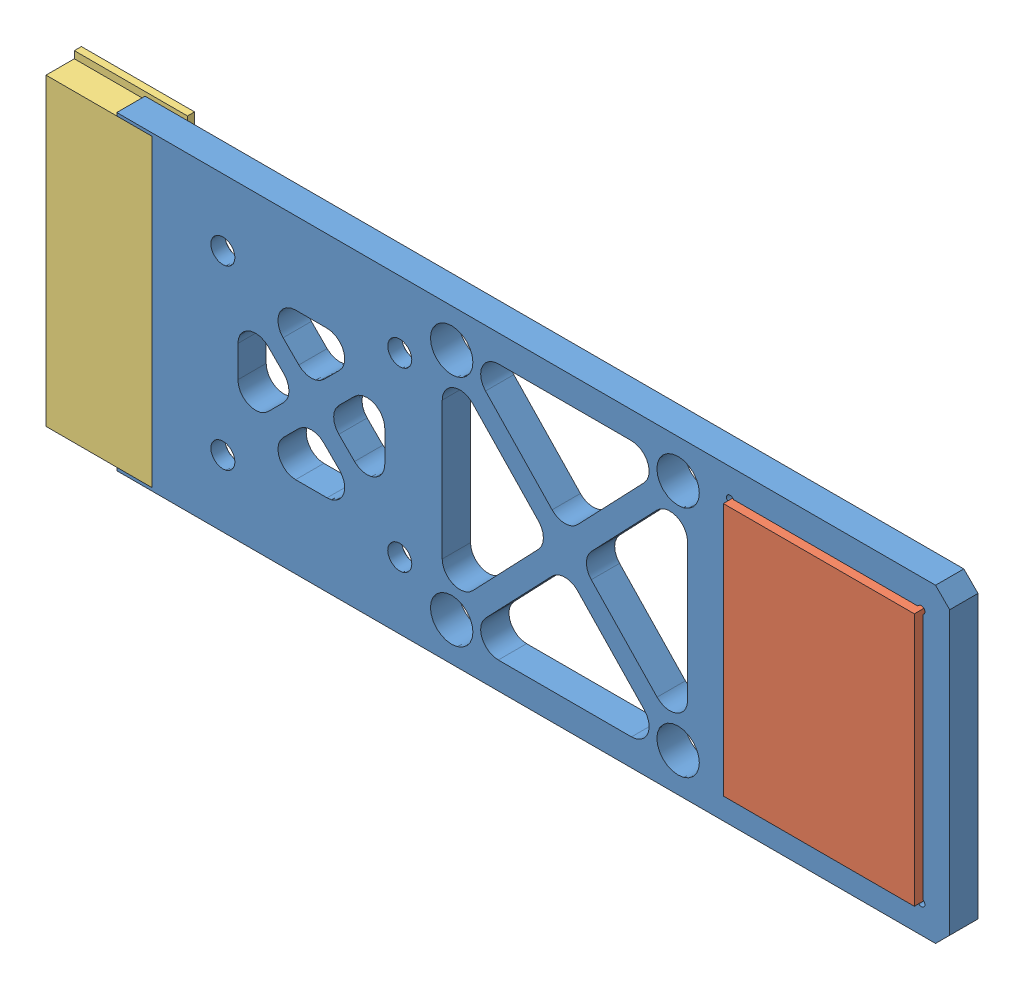
SolidWorks assembly mla_holder_assembly, configuration 默认. Lengths in mm.
Overall size (127.73 45 6).
3 component instances, 3 part files, 6 mates.
Components (placement in the parent):
- MLAHolder_xmt-1: MLAHolder_xmt [Default] at origin size (117.72 43.85 4)
- MicroLens-1: MicroLens [Default] at (90.225 21.95 3) x (0 -1 0) z (0 0 1) size (35.8 27 2)
- balance_weight_s-1: balance_weight_s [默认] at (-12.5 21.925 4) x (1 0 0) z (0 0 -1) size (16 45 5)
Mates (geometry in assembly coordinates):
- 重合1: coincident: plane of MLAHolder_xmt-1 through (76.675 39.85 3) normal (0 0 1); plane of MicroLens-1 through (90.225 21.95 3) normal (0 0 -1)
- 重合2: coincident: plane of MLAHolder_xmt-1 through (76.675 39.85 4) normal (0 -1 0); plane of MicroLens-1 through (103.725 39.85 5) normal (0 1 0)
- 重合3: coincident: plane of MLAHolder_xmt-1 through (103.725 39.85 4) normal (-1 0 0); plane of MicroLens-1 through (103.725 39.85 5) normal (1 0 0)
- 重合6: coincident: plane of MLAHolder_xmt-1 through (0 0 0) normal (0 0 -1); plane of balance_weight_s-1 through (-12.5 21.925 0) normal (0 0 1)
- 重合7: coincident: plane of MLAHolder_xmt-1 through (-5 0.425 4) normal (-1 0 0); plane of balance_weight_s-1 through (-5 0.425 0) normal (1 0 0)
- 重合8: coincident: plane of MLAHolder_xmt-1 through (-10 0.425 4) normal (0 1 0); plane of balance_weight_s-1 through (-20 0.425 0) normal (0 -1 0)
